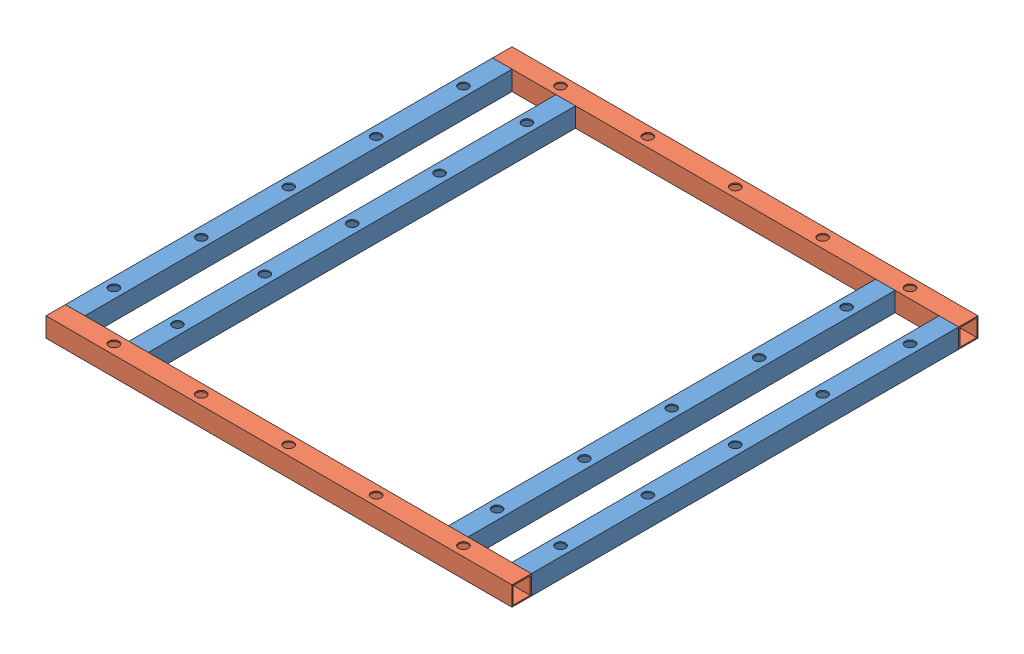
SolidWorks assembly topPlate, configuration Default. Lengths in mm.
Overall size (609.6 25.4 609.6).
6 component instances, 2 part files, 18 mates.
Components (placement in the parent):
- 22_stube-1: 22_stube [Default] at (12.7 0 571.5) x (1 0 0) z (0 1 0) size (25.4 558.8 25.4)
- 22_stube-2: 22_stube [Default] at (95.758 0 571.5) x (1 0 0) z (0 1 0) size (25.4 558.8 25.4)
- 22_stube-3: 22_stube [Default] at (596.9 0 571.5) x (1 0 0) z (0 1 0) size (25.4 558.8 25.4)
- 22_stube-4: 22_stube [Default] at (513.842 0 571.5) x (1 0 0) z (0 1 0) size (25.4 558.8 25.4)
- 24_stube-1: 24_stube [Default] x (0 -1 0) z (0 0 1) size (25.4 609.6 25.4)
- 24_stube-2: 24_stube [Default] at (609.6 0 584.2) x (0 1 0) z (0 0 1) size (25.4 609.6 25.4)
Mates (geometry in assembly coordinates):
- Coincident21: coincident: point of 24_stube-1; point of assembly
- Parallel3: parallel aligned: plane of 24_stube-1 through (609.6 12.7 12.7) normal (0 0 1); plane of assembly through (0 0 0) normal (0 0 1)
- Parallel4: parallel anti-aligned: plane of 24_stube-1 through (609.6 -12.7 12.7) normal (0 -1 0); plane of assembly through (0 0 0) normal (0 1 0)
- Coincident24: coincident anti-aligned: plane of 22_stube-1 through (12.7 0 12.7) normal (0 0 -1); plane of 24_stube-1 through (609.6 12.7 12.7) normal (0 0 1)
- Coincident25: coincident anti-aligned: plane of 22_stube-2 through (95.758 0 12.7) normal (0 0 -1); plane of 24_stube-1 through (609.6 12.7 12.7) normal (0 0 1)
- Coincident26: coincident anti-aligned: plane of 22_stube-3 through (596.9 0 12.7) normal (0 0 -1); plane of 24_stube-1 through (609.6 12.7 12.7) normal (0 0 1)
- Coincident27: coincident anti-aligned: plane of 22_stube-4 through (513.842 0 12.7) normal (0 0 -1); plane of 24_stube-1 through (609.6 12.7 12.7) normal (0 0 1)
- Coincident28: coincident aligned: plane of 24_stube-1 through (609.6 12.7 12.7) normal (0 1 0); plane of 24_stube-2 through (0 12.7 596.9) normal (0 1 0)
- Coincident29: coincident anti-aligned: plane of 22_stube-3 through (596.9 0 571.5) normal (0 0 1); plane of 24_stube-2 through (0 -12.7 571.5) normal (0 0 -1)
- Coincident30: coincident aligned: plane of 24_stube-1 through (609.6 0 0) normal (1 0 0); plane of 24_stube-2 through (609.6 0 584.2) normal (1 0 0)
- Coincident31: coincident aligned: plane of 22_stube-3 through (609.6 12.7 12.7) normal (1 0 0); plane of 24_stube-1 through (609.6 0 0) normal (1 0 0)
- Coincident32: coincident aligned: plane of 22_stube-3 through (584.2 12.7 12.7) normal (0 1 0); plane of 24_stube-1 through (609.6 12.7 12.7) normal (0 1 0)
- Coincident33: coincident aligned: plane of 22_stube-4 through (501.142 12.7 12.7) normal (0 1 0); plane of 24_stube-1 through (609.6 12.7 12.7) normal (0 1 0)
- Coincident34: coincident aligned: plane of 22_stube-2 through (83.058 12.7 12.7) normal (0 1 0); plane of 24_stube-1 through (609.6 12.7 12.7) normal (0 1 0)
- Coincident35: coincident aligned: plane of 22_stube-1 through (0 12.7 12.7) normal (0 1 0); plane of 24_stube-1 through (609.6 12.7 12.7) normal (0 1 0)
- Coincident36: coincident aligned: plane of 22_stube-1 through (0 12.7 12.7) normal (-1 0 0); plane of 24_stube-1 through (0 0 0) normal (-1 0 0)
- Distance1: distance = 57.658 mm anti-aligned: plane of 22_stube-1 through (25.4 12.7 12.7) normal (1 0 0); plane of 22_stube-2 through (83.058 12.7 12.7) normal (-1 0 0)
- Distance2: distance = 57.658 mm anti-aligned: plane of 22_stube-4 through (526.542 12.7 12.7) normal (1 0 0); plane of 22_stube-3 through (584.2 12.7 12.7) normal (-1 0 0)
